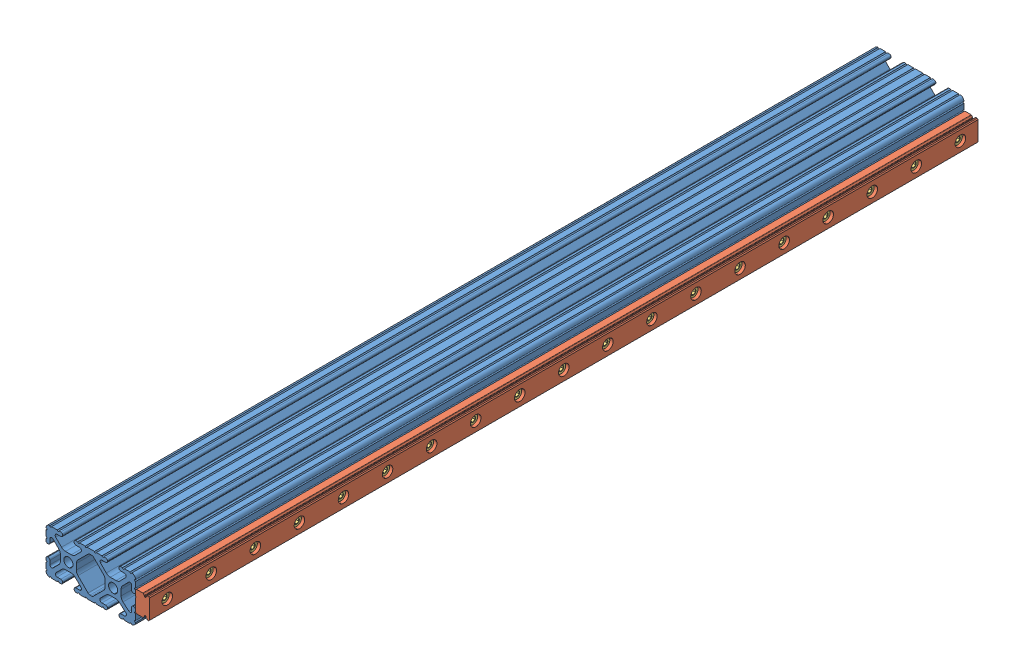
SolidWorks assembly Rail Mount, configuration Default. Lengths in mm.
Overall size (58.8 25.4 470).
40 component instances, 4 part files, 13 mates.
Components (placement in the parent):
- 1020 Rail Support-1: 1020 Rail Support [1020] at (12.7 0 0) size (50.8 25.4 470)
- Hiwin-MGNR12R470CM-1: Hiwin-MGNR12R470CM [Default] at (25.4 0 225) x (0 0 -1) z (1 0 0) size (470 12 8.07)
- 91290A115_M3x10 BLACK-OXIDE CLASS 12.9 SOCKET HEAD CAP SCREW-20: 91290A115_M3x10 BLACK-OXIDE CLASS 12.9 SOCKET HEAD CAP SCREW [91290A115] at (18.9 0 225) x (0 0 1) z (-1 0 0) size (5.5 5.5 13.21)
- 91290A115_M3x10 BLACK-OXIDE CLASS 12.9 SOCKET HEAD CAP SCREW-21: 91290A115_M3x10 BLACK-OXIDE CLASS 12.9 SOCKET HEAD CAP SCREW [91290A115] at (18.9 0 200) x (0 0 1) z (-1 0 0) size (5.5 5.5 13.21)
- 91290A115_M3x10 BLACK-OXIDE CLASS 12.9 SOCKET HEAD CAP SCREW-22: 91290A115_M3x10 BLACK-OXIDE CLASS 12.9 SOCKET HEAD CAP SCREW [91290A115] at (18.9 0 175) x (0 0 1) z (-1 0 0) size (5.5 5.5 13.21)
- 91290A115_M3x10 BLACK-OXIDE CLASS 12.9 SOCKET HEAD CAP SCREW-23: 91290A115_M3x10 BLACK-OXIDE CLASS 12.9 SOCKET HEAD CAP SCREW [91290A115] at (18.9 0 150) x (0 0 1) z (-1 0 0) size (5.5 5.5 13.21)
- 91290A115_M3x10 BLACK-OXIDE CLASS 12.9 SOCKET HEAD CAP SCREW-24: 91290A115_M3x10 BLACK-OXIDE CLASS 12.9 SOCKET HEAD CAP SCREW [91290A115] at (18.9 0 125) x (0 0 1) z (-1 0 0) size (5.5 5.5 13.21)
- 91290A115_M3x10 BLACK-OXIDE CLASS 12.9 SOCKET HEAD CAP SCREW-25: 91290A115_M3x10 BLACK-OXIDE CLASS 12.9 SOCKET HEAD CAP SCREW [91290A115] at (18.9 0 100) x (0 0 1) z (-1 0 0) size (5.5 5.5 13.21)
- 91290A115_M3x10 BLACK-OXIDE CLASS 12.9 SOCKET HEAD CAP SCREW-26: 91290A115_M3x10 BLACK-OXIDE CLASS 12.9 SOCKET HEAD CAP SCREW [91290A115] at (18.9 0 75) x (0 0 1) z (-1 0 0) size (5.5 5.5 13.21)
- 91290A115_M3x10 BLACK-OXIDE CLASS 12.9 SOCKET HEAD CAP SCREW-27: 91290A115_M3x10 BLACK-OXIDE CLASS 12.9 SOCKET HEAD CAP SCREW [91290A115] at (18.9 0 50) x (0 0 1) z (-1 0 0) size (5.5 5.5 13.21)
- 91290A115_M3x10 BLACK-OXIDE CLASS 12.9 SOCKET HEAD CAP SCREW-28: 91290A115_M3x10 BLACK-OXIDE CLASS 12.9 SOCKET HEAD CAP SCREW [91290A115] at (18.9 0 25) x (0 0 1) z (-1 0 0) size (5.5 5.5 13.21)
- 91290A115_M3x10 BLACK-OXIDE CLASS 12.9 SOCKET HEAD CAP SCREW-29: 91290A115_M3x10 BLACK-OXIDE CLASS 12.9 SOCKET HEAD CAP SCREW [91290A115] at (18.9 0 0) x (0 0 1) z (-1 0 0) size (5.5 5.5 13.21)
- 91290A115_M3x10 BLACK-OXIDE CLASS 12.9 SOCKET HEAD CAP SCREW-30: 91290A115_M3x10 BLACK-OXIDE CLASS 12.9 SOCKET HEAD CAP SCREW [91290A115] at (18.9 0 -25) x (0 0 1) z (-1 0 0) size (5.5 5.5 13.21)
- 91290A115_M3x10 BLACK-OXIDE CLASS 12.9 SOCKET HEAD CAP SCREW-31: 91290A115_M3x10 BLACK-OXIDE CLASS 12.9 SOCKET HEAD CAP SCREW [91290A115] at (18.9 0 -50) x (0 0 1) z (-1 0 0) size (5.5 5.5 13.21)
- 91290A115_M3x10 BLACK-OXIDE CLASS 12.9 SOCKET HEAD CAP SCREW-32: 91290A115_M3x10 BLACK-OXIDE CLASS 12.9 SOCKET HEAD CAP SCREW [91290A115] at (18.9 0 -75) x (0 0 1) z (-1 0 0) size (5.5 5.5 13.21)
- 91290A115_M3x10 BLACK-OXIDE CLASS 12.9 SOCKET HEAD CAP SCREW-33: 91290A115_M3x10 BLACK-OXIDE CLASS 12.9 SOCKET HEAD CAP SCREW [91290A115] at (18.9 0 -100) x (0 0 1) z (-1 0 0) size (5.5 5.5 13.21)
- 91290A115_M3x10 BLACK-OXIDE CLASS 12.9 SOCKET HEAD CAP SCREW-34: 91290A115_M3x10 BLACK-OXIDE CLASS 12.9 SOCKET HEAD CAP SCREW [91290A115] at (18.9 0 -125) x (0 0 1) z (-1 0 0) size (5.5 5.5 13.21)
- 91290A115_M3x10 BLACK-OXIDE CLASS 12.9 SOCKET HEAD CAP SCREW-35: 91290A115_M3x10 BLACK-OXIDE CLASS 12.9 SOCKET HEAD CAP SCREW [91290A115] at (18.9 0 -150) x (0 0 1) z (-1 0 0) size (5.5 5.5 13.21)
- 91290A115_M3x10 BLACK-OXIDE CLASS 12.9 SOCKET HEAD CAP SCREW-36: 91290A115_M3x10 BLACK-OXIDE CLASS 12.9 SOCKET HEAD CAP SCREW [91290A115] at (18.9 0 -175) x (0 0 1) z (-1 0 0) size (5.5 5.5 13.21)
- 91290A115_M3x10 BLACK-OXIDE CLASS 12.9 SOCKET HEAD CAP SCREW-37: 91290A115_M3x10 BLACK-OXIDE CLASS 12.9 SOCKET HEAD CAP SCREW [91290A115] at (18.9 0 -200) x (0 0 1) z (-1 0 0) size (5.5 5.5 13.21)
- 91290A115_M3x10 BLACK-OXIDE CLASS 12.9 SOCKET HEAD CAP SCREW-38: 91290A115_M3x10 BLACK-OXIDE CLASS 12.9 SOCKET HEAD CAP SCREW [91290A115] at (18.9 0 -225) x (0 0 1) z (-1 0 0) size (5.5 5.5 13.21)
- M3 T slot nut-ebay262350716437-1: M3 T slot nut-ebay262350716437 [Default] at (23.6902 0 228) x (0 1 0) z (0 0 -1) size (10 4 6)
- M3 T slot nut-ebay262350716437-2: M3 T slot nut-ebay262350716437 [Default] at (23.6902 0 203) x (0 1 0) z (0 0 -1) size (10 4 6)
- M3 T slot nut-ebay262350716437-3: M3 T slot nut-ebay262350716437 [Default] at (23.6902 0 178) x (0 1 0) z (0 0 -1) size (10 4 6)
- M3 T slot nut-ebay262350716437-4: M3 T slot nut-ebay262350716437 [Default] at (23.6902 0 153) x (0 1 0) z (0 0 -1) size (10 4 6)
- M3 T slot nut-ebay262350716437-5: M3 T slot nut-ebay262350716437 [Default] at (23.6902 0 128) x (0 1 0) z (0 0 -1) size (10 4 6)
- M3 T slot nut-ebay262350716437-6: M3 T slot nut-ebay262350716437 [Default] at (23.6902 0 103) x (0 1 0) z (0 0 -1) size (10 4 6)
- M3 T slot nut-ebay262350716437-7: M3 T slot nut-ebay262350716437 [Default] at (23.6902 0 78) x (0 1 0) z (0 0 -1) size (10 4 6)
- M3 T slot nut-ebay262350716437-8: M3 T slot nut-ebay262350716437 [Default] at (23.6902 0 53) x (0 1 0) z (0 0 -1) size (10 4 6)
- M3 T slot nut-ebay262350716437-9: M3 T slot nut-ebay262350716437 [Default] at (23.6902 0 28) x (0 1 0) z (0 0 -1) size (10 4 6)
- M3 T slot nut-ebay262350716437-10: M3 T slot nut-ebay262350716437 [Default] at (23.6902 0 3) x (0 1 0) z (0 0 -1) size (10 4 6)
- M3 T slot nut-ebay262350716437-11: M3 T slot nut-ebay262350716437 [Default] at (23.6902 0 -22) x (0 1 0) z (0 0 -1) size (10 4 6)
- M3 T slot nut-ebay262350716437-12: M3 T slot nut-ebay262350716437 [Default] at (23.6902 0 -47) x (0 1 0) z (0 0 -1) size (10 4 6)
- M3 T slot nut-ebay262350716437-13: M3 T slot nut-ebay262350716437 [Default] at (23.6902 0 -72) x (0 1 0) z (0 0 -1) size (10 4 6)
- M3 T slot nut-ebay262350716437-14: M3 T slot nut-ebay262350716437 [Default] at (23.6902 0 -97) x (0 1 0) z (0 0 -1) size (10 4 6)
- M3 T slot nut-ebay262350716437-15: M3 T slot nut-ebay262350716437 [Default] at (23.6902 0 -122) x (0 1 0) z (0 0 -1) size (10 4 6)
- M3 T slot nut-ebay262350716437-16: M3 T slot nut-ebay262350716437 [Default] at (23.6902 0 -147) x (0 1 0) z (0 0 -1) size (10 4 6)
- M3 T slot nut-ebay262350716437-17: M3 T slot nut-ebay262350716437 [Default] at (23.6902 0 -172) x (0 1 0) z (0 0 -1) size (10 4 6)
- M3 T slot nut-ebay262350716437-18: M3 T slot nut-ebay262350716437 [Default] at (23.6902 0 -197) x (0 1 0) z (0 0 -1) size (10 4 6)
- M3 T slot nut-ebay262350716437-19: M3 T slot nut-ebay262350716437 [Default] at (23.6902 0 -222) x (0 1 0) z (0 0 -1) size (10 4 6)
Mates (geometry in assembly coordinates):
- Coincident1: coincident aligned: plane of 1020 Rail Support-1 through (12.7 0 0) normal (0 1 0); plane of assembly through (0 0 0) normal (0 1 0)
- Coincident2: coincident: moEndPointRef_w of 1020 Rail Support-1; plane of assembly
- Parallel1: parallel aligned: plane of 1020 Rail Support-1 through (25.4 6.3332 -235) normal (1 0 0); plane of assembly through (0 0 0) normal (1 0 0)
- Coincident4: coincident: moEndPointRef_w of 1020 Rail Support-1; plane of assembly
- Parallel2: parallel aligned: plane of 1020 Rail Support-1 through (16.9875 11.651 235) normal (0 0 1); plane of assembly through (0 0 0) normal (0 0 1)
- Coincident5: coincident anti-aligned: plane of 1020 Rail Support-1 through (25.4 6.3332 -235) normal (1 0 0); plane of Hiwin-MGNR12R470CM-1 through (25.4 1.6 -235) normal (-1 0 0)
- Coincident6: coincident aligned: plane of 1020 Rail Support-1 through (16.9875 11.651 235) normal (0 0 1); plane of Hiwin-MGNR12R470CM-1 through (29.5421 -5.75 235) normal (0 0 1)
- Coincident7: coincident aligned: plane of Hiwin-MGNR12R470CM-1; plane of assembly through (0 0 0) normal (0 1 0)
- Coincident8: coincident anti-aligned: plane of Hiwin-MGNR12R470CM-1 through (28.9 0 223.25) normal (1 0 0); plane of 91290A115_M3x10 BLACK-OXIDE CLASS 12.9 SOCKET HEAD CAP SCREW-20 through (28.9 0 225) normal (-1 0 0)
- Concentric1: concentric anti-aligned: cylinder of Hiwin-MGNR12R470CM-1 through (33.4 0 225) axis (1 0 0) radius 3; cylinder of 91290A115_M3x10 BLACK-OXIDE CLASS 12.9 SOCKET HEAD CAP SCREW-20 through (31.9 0 225) axis (-1 0 0) radius 2.75
- Coincident9: coincident anti-aligned: plane of 1020 Rail Support-1 through (23.1902 6.6769 -235) normal (-1 0 0); plane of M3 T slot nut-ebay262350716437-1 through (23.1902 3.1 222) normal (1 0 0)
- Concentric2: concentric aligned: cylinder of M3 T slot nut-ebay262350716437-1 through (23.6902 0 225) axis (1 0 0) radius 1.25; cylinder of Hiwin-MGNR12R470CM-1 through (33.4 0 225) axis (1 0 0) radius 3
- Parallel3: parallel aligned: plane of M3 T slot nut-ebay262350716437-1 through (23.6902 0 228) normal (0 0 1); plane of 1020 Rail Support-1 through (16.9875 11.651 235) normal (0 0 1)
